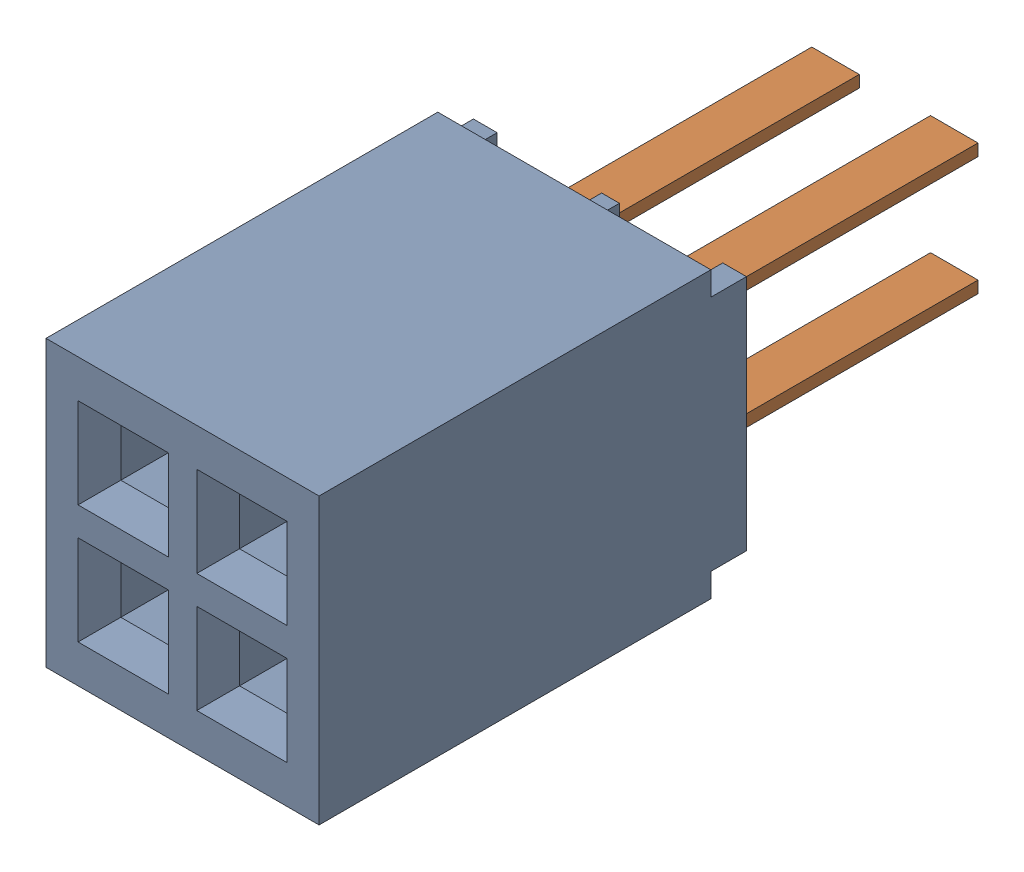
SolidWorks assembly J5, configuration ﾃﾞﾌｫﾙﾄ. Lengths in mm.
Overall size (2.92 3.05 7.62).
3 component instances, 2 part files, 0 mates.
Components (placement in the parent):
- SFMC-102-01-L-D-1: SFMC-102-01-L-D [ﾃﾞﾌｫﾙﾄ] at (74.935 40.97 0) x (-1 0 0) z (0 1 0) size (2.92 7.62 3.05)
  - _SFMC-102-01_socket-1: _SFMC-102-01_socket [ﾃﾞﾌｫﾙﾄ] at origin size (2.92 4.57 3.05)
  - _C-02-01_spins-1: _C-02-01_spins [ﾃﾞﾌｫﾙﾄ] at origin size (1.78 3.81 1.78)
